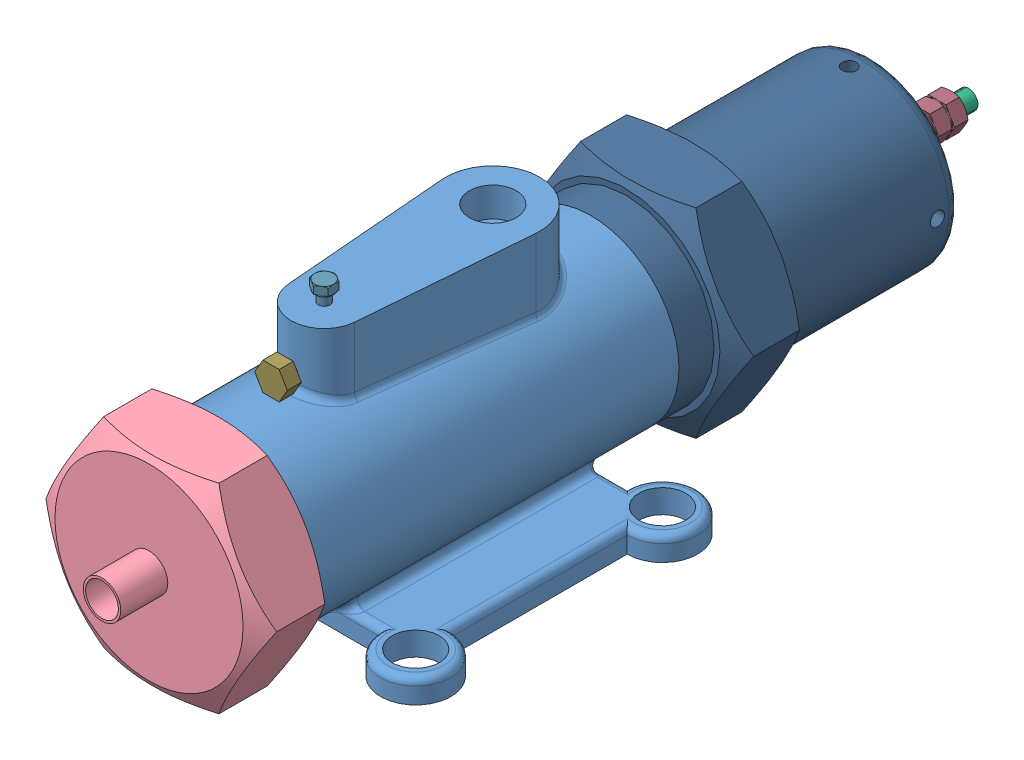
SolidWorks assembly ГТК 025.000.000 СБ - Регулятор Давления, configuration По умолчанию. Lengths in mm.
Overall size (135 134.67 368.81).
17 component instances, 14 part files, 35 mates.
Components (placement in the parent):
- ГТК 025.000.01 - Корпус-1: ГТК 025.000.01 - Корпус [По умолчанию] at origin size (135 105.1 156)
- ГТК 025.000.05 - Седло левое-1: ГТК 025.000.05 - Седло левое [По умолчанию] at (52.5 42.5481 0.0403) x (0 0 -1) z (-0.237066 0.971494 0) size (8 45.1 45.1)
- ГТК 025.000.07 - Прокладка-1: ГТК 025.000.07 - Прокладка [По умолчанию] at (52.5 42.5481 30) x (1 0 0) z (0 1 0) size (75.1 1 75.1)
- ГТК 025.000.02 - Штуцер-1: ГТК 025.000.02 - Штуцер [По умолчанию] at (52.5 42.5481 45.5) x (0.866025 0.5 0) z (0.5 -0.866025 0) size (85 80.96 98.15)
- ГТК 025.002.00 - Клапан в сборе-1: ГТК 025.002.00 - Клапан в сборе [По умолчанию] at (52.5 42.5481 -4.1847) x (0 0 -1) z (-0.291847 -0.956465 0) size (283.63 39.1 39.1)
  - ГТК 025.002.01 - Клапан-1: ГТК 025.002.01 - Клапан [По умолчанию] at origin size (83.63 39.1 39.1)
  - ГТК 025.002.02 - Шток-1: ГТК 025.002.02 - Шток [По умолчанию] at (75.6262 0 0) x (1 0 0) z (0 -0.967929 0.251224) size (208 22 22)
- ГТК 025.001.00 - Цилиндр в сборе-1: ГТК 025.001.00 - Цилиндр в сборе [По умолчанию] at (52.5 42.5481 -99.9597) x (0 0 -1) z (1 0 0) size (139.25 55.1 55.1)
  - ГТК 025.001.01 - Цилиндр-1: ГТК 025.001.01 - Цилиндр [По умолчанию] at origin size (129.25 55.1 55.1)
  - ГТК 025.001.02 - Втулка-1: ГТК 025.001.02 - Втулка [По умолчанию] at (97.25 0 0) x (0 0 1) z (0 1 0) size (33.1 42 33.1)
- ГТК 025.000.04 - Седло Правое-1: ГТК 025.000.04 - Седло Правое [По умолчанию] at (52.5 42.5481 -93.9597) x (0 0 -1) z (0.919247 0.393682 0) size (6 51.1 51.1)
- ГТК 025.000.03 - Стакан-1: ГТК 025.000.03 - Стакан [По умолчанию] at (52.5 42.5481 -157) x (0 1 0) z (1 0 0) size (85 130 98.15)
- ГТК 025.000.08 - Пружинка-1: ГТК 025.000.08 - Пружинка [L1] at (52.5 42.5481 -197.2108) x (-0.572014 0.820244 0) z (0.820244 0.572014 0) size (15.49 114.16 15.4)
- ГТК 025.000.06 - Игла-1: ГТК 025.000.06 - Игла [По умолчанию] at (52.5 87.0962 6.0672) x (0.866025 0.5 0) z (-0.5 0.866025 0) size (12 31.5 13.86)
- nut m8 iso 4032-3: nut m8 iso 4032 [ISO - 4032 - M8 - W - N] at (52.5 42.5481 -273.8) x (-0.866025 -0.5 0) z (0 0 -1) size (13 15.01 6.8)
- nut m8 iso 4032-4: nut m8 iso 4032 [ISO - 4032 - M8 - W - N] at (52.5 42.5481 -280.6) x (0.866025 -0.5 0) z (0 0 -1) size (13 15.01 6.8)
- hex screw m5-3: hex screw m5 [ISO 4018 - M5 x 20-WN] at (52.5 113.4712 -13.56) x (0 -1 0) z (1 0 0) size (23.88 9.24 8)
Mates (geometry in assembly coordinates):
- Совпадение1: coincident anti-aligned: plane of Корпус-1 through (52.5 23 -7.9597) normal (0 0 1); plane of Левое седло-1 through (57.8458 20.6409 -7.9597) normal (0 0 -1)
- Концентричный1: concentric aligned: circle of Корпус-1; circle of Левое седло-1
- Совпадение2: coincident anti-aligned: plane of Корпус-1 through (52.5 15 29) normal (0 0 1); plane of Прокладка-1 through (52.5 42.5481 29) normal (0 0 -1)
- Концентричный2: concentric anti-aligned: circle of Корпус-1; circle of Прокладка-1
- Совпадение3: coincident anti-aligned: plane of Прокладка-1 through (52.5 42.5481 30) normal (0 0 1); plane of Штуцер-1 through (52.5 42.5481 30) normal (0 0 -1)
- Концентричный3: concentric aligned: circle of Прокладка-1; circle of Штуцер-1
- Совпадение4: coincident aligned: cone of Левое седло-1 through (52.5 42.5481 -4.1847) axis (0 0 1); cone of ГТК 025.002.00 - Клапан в сборе-1/Клапан-1 through (52.5 42.5481 -9.1847) axis (0 0 1)
- Концентричный4: concentric anti-aligned: circle of ГТК 025.002.00 - Клапан в сборе-1/Шток-1; circle of ГТК 025.001.00 - Цилиндр в сборе-1/Втулка-1
- Параллельность1: parallel aligned: plane of ГТК 025.001.00 - Цилиндр в сборе-1/Втулка-1 through (37.7469 50.0481 -239.2097) normal (0 1 0)
- Совпадение7: coincident anti-aligned: plane of Корпус-1 through (52.5 12.5 -93.9597) normal (0 0 -1); plane of Правое седло-1 through (29.0133 32.4895 -93.9597) normal (0 0 1)
- Концентричный6: concentric aligned: circle of Корпус-1; circle of Правое седло-1
- Совпадение8: coincident anti-aligned: plane of ГТК 025.001.00 - Цилиндр в сборе-1/Цилиндр-1 through (35.95 42.5481 -99.9597) normal (0 0 1); plane of Правое седло-1 through (36.3672 35.639 -99.9597) normal (0 0 -1)
- Совпадение9: coincident anti-aligned: plane of Корпус-1 through (52.5 5 -127) normal (0 0 -1); plane of ГТК 025.000.03 - Стакан-1 through (52.5 42.5481 -127) normal (0 0 1)
- Концентричный7: concentric aligned: circle of Корпус-1; circle of Стакан-1
- Концентричный8: concentric aligned: cylinder of ГТК 025.002.00 - Клапан в сборе-1/Шток-1 through (52.5 42.5481 -287.8108) axis (0 0 -1) radius 4; line of Пружинка-1 through (52.5 42.5481 -147.2108) axis (0 0 -1)
- Совпадение11: coincident anti-aligned: plane of ГТК 025.002.00 - Клапан в сборе-1/Шток-1 through (63.4902 42.0839 -90.8108) normal (0 0 -1); plane of Пружинка-1 through (52.5 42.5481 -90.8108) normal (0 0 1)
- Параллельность2: parallel aligned: plane of ГТК 025.001.00 - Цилиндр в сборе-1 through (52.5 42.5481 -99.9597) normal (0 1 0); plane of ГТК 025.000.03 - Стакан-1 through (77.0374 85.0481 -142) normal (0 1 0)
- Параллельность3: parallel aligned: plane of Штуцер-1 through (77.0374 85.0481 61) normal (0 1 0); plane of ГТК 025.000.03 - Стакан-1 through (77.0374 85.0481 -142) normal (0 1 0)
- Концентричный9: concentric aligned: cylinder of Корпус-1 through (52.5 87.0962 -127.001) axis (0 0 1) radius 2.5; cylinder of Игла-1 through (52.5 87.0962 -17.4328) axis (0 0 1) radius 2.5
- Параллельность4: parallel aligned: plane of Штуцер-1 through (77.0374 85.0481 61) normal (0 1 0); plane of Игла-1 through (49.0359 93.0962 3.0672) normal (0 1 0)
- Расстояние3: distance = 2.5 mm anti-aligned: cylinder of Корпус-1 through (52.5 105.0962 -13.56) axis (0 -1 0) radius 14.1272; plane of Игла-1 through (52.5 87.0962 3.0672) normal (0 0 -1)
- Концентричный14: concentric aligned: cylinder of ГТК 025.002.00 - Клапан в сборе-1/Шток-1 through (52.5 42.5481 -287.8108) axis (0 0 -1) radius 4; cylinder of hex nut style 1 gradeab_iso-3 through (52.5 42.5481 -248.7625) axis (0 0 -1) radius 4
- Концентричный15: concentric anti-aligned: cone of hex nut style 1 gradeab_iso-3 through (52.5 42.5481 -273.3379) axis (0 0 1); cylinder of hex nut style 1 gradeab_iso-4 through (52.5 42.5481 -255.5625) axis (0 0 -1) radius 4
- Совпадение16: coincident anti-aligned: plane of hex nut style 1 gradeab_iso-3 through (48.7472 49.0481 -273.8) normal (0 0 -1); plane of hex nut style 1 gradeab_iso-4 through (48.7472 36.0481 -273.8) normal (0 0 1)
- Концентричный18: concentric aligned: cylinder of Корпус-1 through (52.5 -0.001 -13.56) axis (0 1 0) radius 2.5; cylinder of hex screw gradec_iso-3 through (52.5 113.4712 -13.56) axis (0 1 0) radius 2.5
- Касательность41: tangent anti-aligned: cylinder of Игла-1 through (52.5 87.0962 -17.4328) axis (0 0 1) radius 2.5; plane of hex screw gradec_iso-3 through (52.5 89.5962 -13.56) normal (0 -1 0)
- Параллельность51: parallel aligned: plane of Корпус-1 through (105 10 0) normal (1 0 0); plane of hex screw gradec_iso-3 through (56.5 109.5962 -15.8694) normal (1 0 0)
- Расстояние41: distance = 10 mm anti-aligned: plane of hex nut style 1 gradeab_iso-3 through (48.7472 49.0481 -267) normal (0 0 1); plane of ГТК 025.000.03 - Стакан-1 through (52.5 42.5481 -257) normal (0 0 -1)
- Параллельность61: parallel aligned: plane of ГТК 025.000.03 - Стакан-1 through (77.0374 85.0481 -142) normal (0 1 0); plane of hex nut style 1 gradeab_iso-3 through (48.7472 49.0481 -267) normal (0 1 0)
- Параллельность71: parallel aligned: plane of hex nut style 1 gradeab_iso-3 through (48.7472 49.0481 -267) normal (0 1 0); plane of hex nut style 1 gradeab_iso-4 through (48.7472 49.0481 -273.8) normal (0 1 0)
- Концентричный191: concentric aligned: cylinder of Корпус-1 through (52.5 42.5481 135.4472) axis (0 0 1) radius 19.5481; cylinder of Левое седло-1 through (52.5 42.5481 0.0403) axis (0 0 1) radius 22.55
- Концентричный201: concentric aligned: cylinder of Корпус-1 through (52.5 42.5481 135.4472) axis (0 0 1) radius 27.5481; cylinder of Правое седло-1 through (52.5 42.5481 -93.9597) axis (0 0 1) radius 25.55
- Концентричный211: concentric anti-aligned: cylinder of Корпус-1 through (52.5 42.5481 135.4472) axis (0 0 1) radius 19.5481; cylinder of ГТК 025.002.00 - Клапан в сборе-1/Шток-1 through (52.5 42.5481 -287.8108) axis (0 0 -1) radius 4
- Заблокировать2: lock: unknown of ГТК 025.002.00 - Клапан в сборе-1/Шток-1; unknown of Пружинка-1
- Заблокировать3: lock: unknown of Корпус-1; unknown of Прокладка-1
